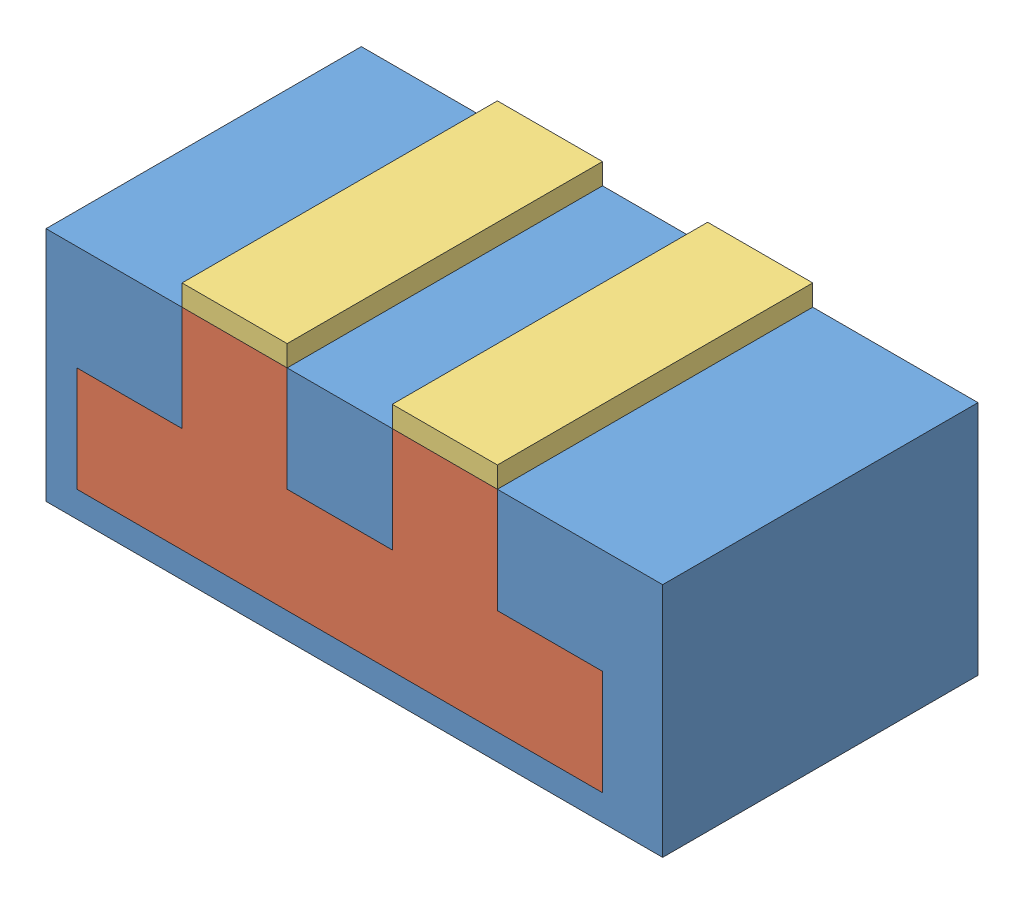
SolidWorks assembly after_metal, configuration Default. Lengths in mm.
Overall size (58.66 24.47 30).
4 component instances, 3 part files, 6 mates.
Components (placement in the parent):
- outer-1: outer [Default] at (-11.5507 1.1875 5.2884) size (58.66 22.47 30)
- inner-1: inner [Default] at (-11.5507 1.1875 5.2884) size (50 20 30)
- metal-2: metal [Default] at (3.4493 22.1875 5.2884) size (10 2 30)
- metal-3: metal [Default] at (23.4493 22.1875 5.2884) size (10 2 30)
Mates (geometry in assembly coordinates):
- Coincident1: coincident anti-aligned: plane of outer-1 through (28.4493 11.1875 35.2884) normal (-1 0 0); plane of inner-1 through (28.4493 11.1875 35.2884) normal (1 0 0)
- Coincident3: coincident aligned: plane of outer-1 through (-11.5507 1.1875 35.2884) normal (0 0 1); plane of inner-1 through (-11.5507 1.1875 35.2884) normal (0 0 1)
- Coincident4: coincident aligned: plane of outer-1 through (-14.4939 21.1875 35.2884) normal (0 1 0); plane of inner-1 through (8.4493 21.1875 35.2884) normal (0 1 0)
- Coincident5: coincident aligned: plane of inner-1 through (-11.5507 1.1875 35.2884) normal (0 0 1); plane of metal-2 through (3.4493 22.1875 35.2884) normal (0 0 1)
- Coincident6: coincident: line of outer-1 through (8.4493 21.1875 35.2884) axis (0 0 -1); plane of metal-2 through (8.4493 21.1875 35.2884) normal (1 0 0)
- Coincident7: coincident anti-aligned: plane of inner-1 through (8.4493 21.1875 35.2884) normal (0 1 0); plane of metal-2 through (-1.5507 21.1875 35.2884) normal (0 -1 0)
